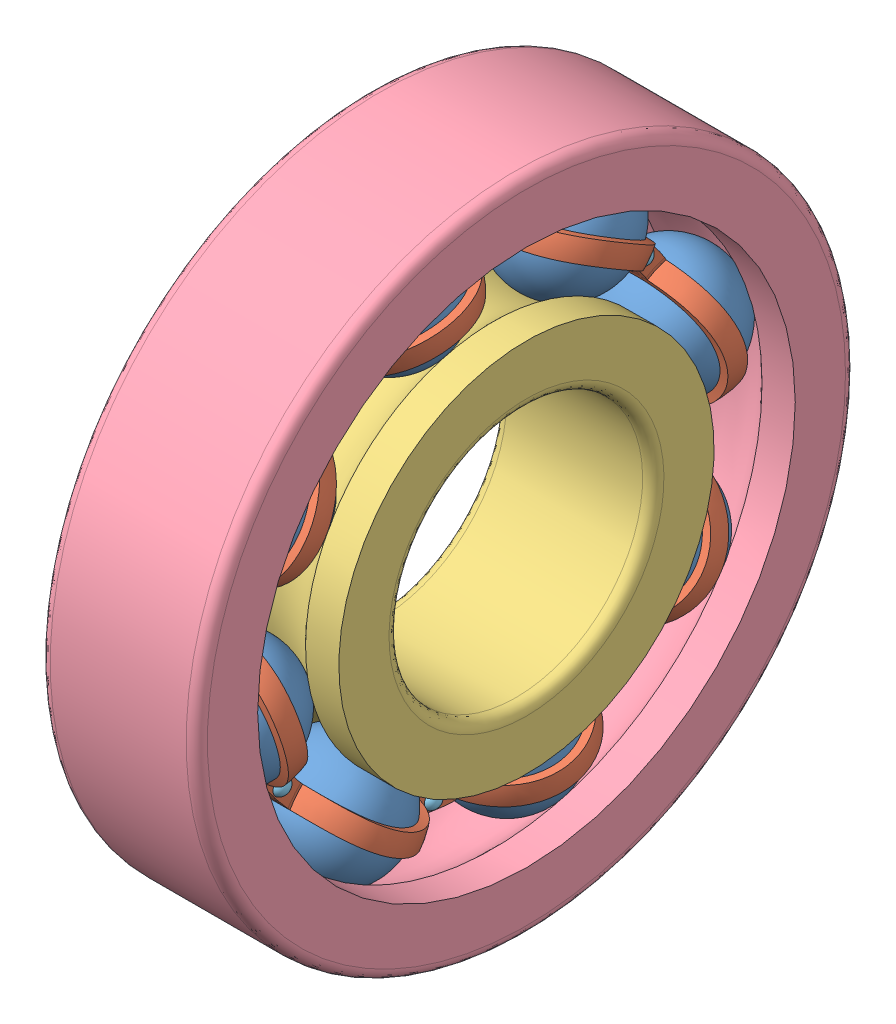
SolidWorks assembly Ball_Bearing, configuration Domyślna. Lengths in mm.
Overall size (31 130 130).
20 component instances, 5 part files, 9 mates.
Components (placement in the parent):
- Ball-1: Ball [Domyślna] at (-76.0796 -19.2421 1.4846) x (1 0 0) z (0 0.500341 0.865828) size (24 24 24)
- Cage-1: Cage [Domyślna] at (-68.0796 -58.2044 24) x (0 0.500341 0.865828) z (-1 0 0) size (94 94 13.65)
- Inner_ring-1: Inner_ring [Domyślna] at (-76.0796 -58.2044 24) x (1 0 0) z (0 0.500341 0.865828) size (31 74 74)
- Outer_ring-2: Outer_ring [Domyślna] at (-76.0796 -58.2044 24) size (31 130 130)
- Ball-2: Ball [Domyślna] at (-76.0796 -46.5746 -19.4713) x (1 0 0) z (0 0.966028 0.258438) size (24 24 24)
- Ball-3: Ball [Domyślna] at (-76.0796 -80.7197 -14.9623) x (1 0 0) z (0 0.865828 -0.500341) size (24 24 24)
- Ball-4: Ball [Domyślna] at (-76.0796 -101.6756 12.3703) x (1 0 0) z (0 0.258438 -0.966028) size (24 24 24)
- Ball-5: Ball [Domyślna] at (-76.0796 -97.1666 46.5154) x (1 0 0) z (0 -0.500341 -0.865828) size (24 24 24)
- Ball-6: Ball [Domyślna] at (-76.0796 -69.8341 67.4713) x (1 0 0) z (0 -0.966028 -0.258438) size (24 24 24)
- Ball-7: Ball [Domyślna] at (-76.0796 -35.689 62.9623) x (1 0 0) z (0 -0.865828 0.500341) size (24 24 24)
- Ball-8: Ball [Domyślna] at (-76.0796 -14.7331 35.6297) x (1 0 0) z (0 -0.258438 0.966028) size (24 24 24)
- Cage-2: Cage [Domyślna] at (-81.0796 -58.2044 24) x (0 -0.500341 -0.865828) z (1 0 0) size (94 94 13.65)
- rivet 02_din-2: rivet 02_din [DIN 660-2x6-St-A-3] at (-76.0796 -64.0956 -20.6127) x (-1 0 0) z (0 0.924225 0.381849) size (5.4 3.5 3.5)
- rivet 02_din-3: rivet 02_din [DIN 660-2x6-St-A-3] at (-76.0796 -30.8242 -11.7117) x (-1 0 0) z (0 0.383517 0.923534) size (5.4 3.5 3.5)
- rivet 02_din-4: rivet 02_din [DIN 660-2x6-St-A-3] at (-76.0796 -13.5917 18.1087) x (-1 0 0) z (0 -0.381849 0.924225) size (5.4 3.5 3.5)
- rivet 02_din-5: rivet 02_din [DIN 660-2x6-St-A-3] at (-76.0796 -22.4927 51.3802) x (-1 0 0) z (0 -0.923534 0.383517) size (5.4 3.5 3.5)
- rivet 02_din-6: rivet 02_din [DIN 660-2x6-St-A-3] at (-76.0796 -52.3131 68.6127) x (-1 0 0) z (0 -0.924225 -0.381849) size (5.4 3.5 3.5)
- rivet 02_din-7: rivet 02_din [DIN 660-2x6-St-A-3] at (-76.0796 -85.5846 59.7117) x (-1 0 0) z (0 -0.383517 -0.923534) size (5.4 3.5 3.5)
- rivet 02_din-8: rivet 02_din [DIN 660-2x6-St-A-3] at (-76.0796 -102.8171 29.8913) x (-1 0 0) z (0 0.381849 -0.924225) size (5.4 3.5 3.5)
- rivet 02_din-9: rivet 02_din [DIN 660-2x6-St-A-3] at (-76.0796 -93.9161 -3.3802) x (-1 0 0) z (0 0.923534 -0.383517) size (5.4 3.5 3.5)
Mates (geometry in assembly coordinates):
- Concentric1: concentric aligned: cylinder of Inner_ring-1 through (-76.0796 -58.2044 24) axis (-1 0 0) radius 25; cylinder of Outer_ring-2 through (-76.0796 -58.2044 24) axis (-1 0 0) radius 65
- Width1: width aligned: plane of Outer_ring-2 through (-91.5796 6.7956 24) normal (-1 0 0); plane of Inner_ring-1 through (-60.5796 6.7956 24) normal (1 0 0); plane of Outer_ring-2 through (-91.5796 -21.2044 23.9964) normal (-1 0 0); plane of Inner_ring-1 through (-60.5796 -21.2044 23.9964) normal (1 0 0)
- Coincident1: coincident aligned: plane of Ball-1; plane of Inner_ring-1
- Coincident2: coincident aligned: plane of Ball-1 through (-76.0796 -13.2044 23.9957) normal (1 0 0); plane of Inner_ring-1 through (-76.0796 -58.2044 24) normal (1 0 0)
- Tangent1: tangent anti-aligned: sphere of Ball-1; torus of Inner_ring-1
- Coincident3: coincident anti-aligned: line of ? through (-76.0796 -58.2044 24) axis (1 0 0); line of ? through (-54.8457 -58.2044 24) axis (-1 0 0)
- Concentric2: concentric: sphere of Ball-1; sphere of Cage-1
- Concentric3: concentric aligned: cylinder of Cage-2 through (-86.5796 -40.9876 -17.5762) axis (1 0 0) radius 1; cylinder of rivet 02_din-2 through (-37.0796 -40.9876 -17.5762) axis (1 0 0) radius 1
- Coincident4: coincident anti-aligned: plane of Cage-2 through (-73.0796 -58.2044 24) normal (1 0 0); plane of rivet 02_din-2 through (-73.0796 -41.3695 -16.652) normal (-1 0 0)
